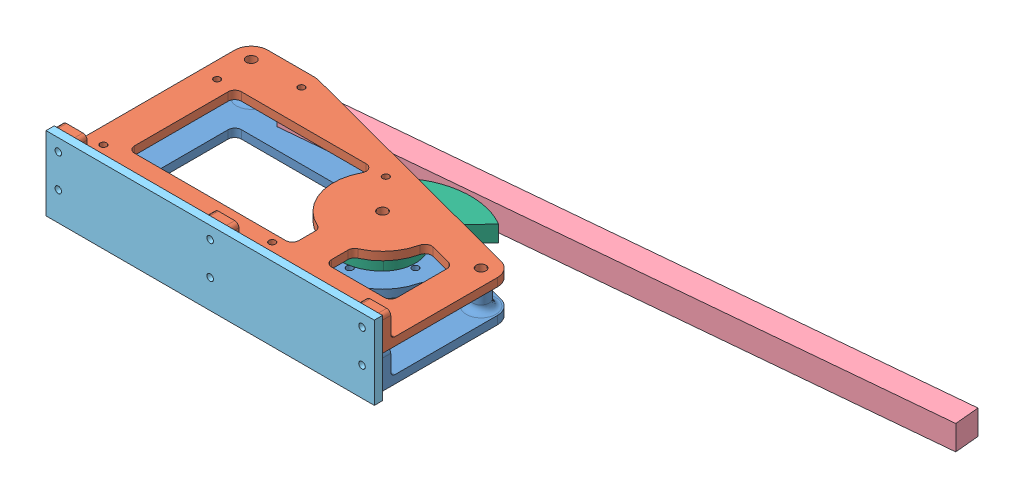
SolidWorks assembly R1_Assy, configuration Default. Lengths in mm.
Overall size (172.85 53.34 91.79).
6 component instances, 6 part files, 14 mates.
Components (placement in the parent):
- Motor_Plate-1: Motor_Plate [Default] at (68.2144 78.3241 104.509) size (127 12.7 76.2)
- Support_Plate-1: Support_Plate [Default] at (68.2144 91.0241 104.509) size (127 12.7 76.2)
- Motor_Enclosure_B-1: Motor_Enclosure_B [Default] at (68.2144 78.3241 104.509) x (-1 0 0) z (0 0 1) size (32 27.94 32)
- Mallet-1: Mallet [Default] at (11.0644 81.4991 78.7348) x (0.995717 0 -0.092456) z (0.092456 0 0.995717) size (152.4 9.53 9.53)
- Base_Plate-1: Base_Plate [Default] at (49.1644 91.0241 152.134) x (1 0 0) z (0 1 0) size (127 3.17 28.57)
- Cam_2-1: Cam_2 [Default] at (68.2144 89.4366 104.509) x (-0.720198 0 -0.693769) z (0 -1 0) size (35.1 48.07 11.11)
Mates (geometry in assembly coordinates):
- Coincident5: coincident anti-aligned: plane of Motor_Plate-1 through (68.2144 78.3241 104.509) normal (0 -1 0); plane of Motor_Enclosure_B-1 through (68.2144 78.3241 104.509) normal (0 1 0)
- Concentric1: concentric anti-aligned: cylinder of Motor_Plate-1 through (68.2144 81.4991 91.809) axis (0 -1 0) radius 1.27; cylinder of Motor_Enclosure_B-1 through (68.2144 75.7841 91.809) axis (0 1 0) radius 1.778
- Concentric2: concentric anti-aligned: cylinder of Motor_Plate-1 through (80.9144 81.4991 104.509) axis (0 -1 0) radius 1.27; cylinder of Motor_Enclosure_B-1 through (80.9144 75.7841 104.509) axis (0 1 0) radius 1.778
- Concentric3: concentric aligned: cylinder of Motor_Plate-1 through (11.0644 81.4991 78.7348) axis (0 -1 0) radius 1.27; cylinder of Mallet-1 through (11.0644 91.0241 78.7348) axis (0 -1 0) radius 1.905
- Distance3: distance = 0 mm anti-aligned: plane of Motor_Plate-1 through (68.2144 81.4991 104.509) normal (0 1 0); plane of Mallet-1 through (11.0644 81.4991 78.7348) normal (0 -1 0)
- Coincident7: coincident aligned: plane of Motor_Plate-1 through (-14.3356 81.4991 72.759) normal (-1 0 0); plane of Support_Plate-1 through (-14.3356 94.1991 72.759) normal (-1 0 0)
- Distance4: distance = 9.525 mm anti-aligned: plane of Motor_Plate-1 through (68.2144 81.4991 104.509) normal (0 1 0); plane of Support_Plate-1 through (68.2144 91.0241 104.509) normal (0 -1 0)
- Coincident9: coincident anti-aligned: plane of Support_Plate-1 through (-14.3356 94.1991 148.959) normal (0 0 1); plane of Base_Plate-1 through (49.1644 91.0241 148.959) normal (0 0 -1)
- Coincident10: coincident aligned: plane of Support_Plate-1 through (112.6644 103.7241 145.784) normal (0 1 0); plane of Base_Plate-1 through (49.1644 103.7241 148.959) normal (0 1 0)
- Coincident11: coincident aligned: plane of Support_Plate-1 through (-14.3356 94.1991 72.759) normal (-1 0 0); plane of Base_Plate-1 through (-14.3356 91.0241 148.959) normal (-1 0 0)
- Coincident14: coincident anti-aligned: plane of Motor_Plate-1 through (-14.3356 81.4991 148.959) normal (0 0 1); plane of Base_Plate-1 through (49.1644 91.0241 148.959) normal (0 0 -1)
- Concentric4: concentric anti-aligned: cylinder of Motor_Plate-1 through (68.2144 81.4991 104.509) axis (0 -1 0) radius 3.175; cylinder of Cam_2-1 through (68.2144 78.3241 104.509) axis (0 1 0) radius 3.175
- Coincident15: coincident anti-aligned: plane of Motor_Enclosure_B-1 through (68.2144 78.3241 104.509) normal (0 1 0); plane of Cam_2-1 through (68.2144 78.3241 104.509) normal (0 -1 0)
- Tangent1: tangent anti-aligned: plane of Mallet-1 through (6.7626 91.0241 83.9172) normal (0.092456 0 0.995717); cylinder of Cam_2-1 through (75.4728 83.0866 107.0613) axis (0 1 0) radius 29.3976
